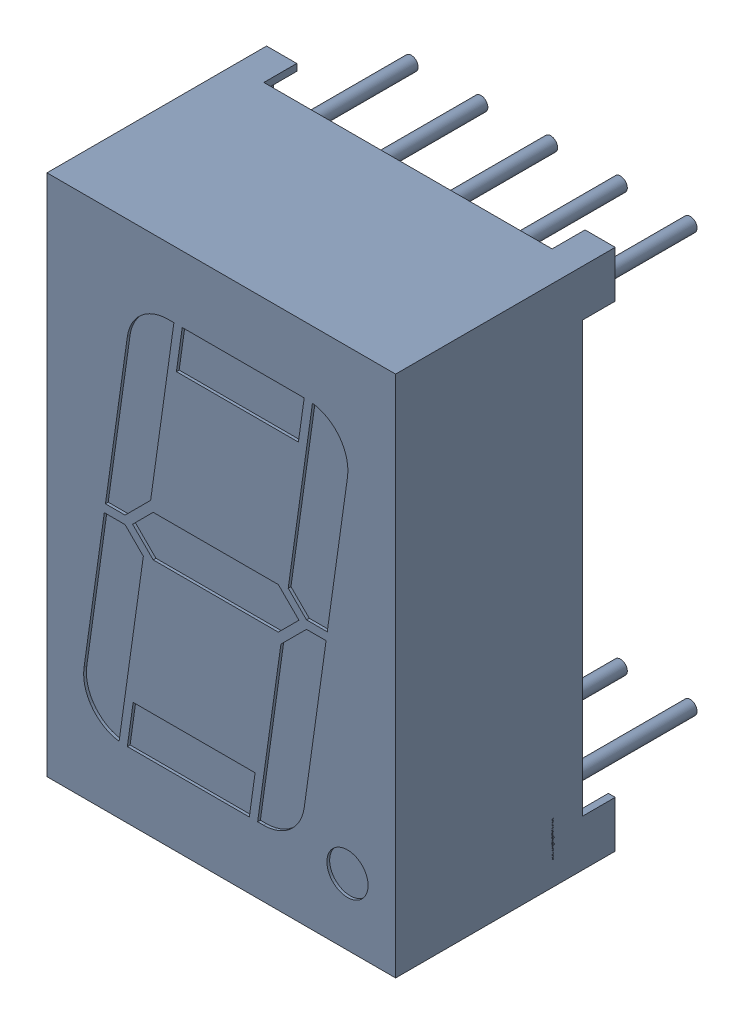
SolidWorks assembly Disp_SA56-11.1, configuration Default. Lengths in mm.
Overall size (12.7 19.05 12).
3 component instances, 1 part files, 0 mates.
Components (placement in the parent):
- SW3dPS-Disp_SA56-11-1: SW3dPS-Disp_SA56-11 [Default] at origin size (12.7 19.05 12)
  - SW3dPS-Disp_SA56-11_Open_CASCADE_STEP_translator_6.2_78.2-1: SW3dPS-Disp_SA56-11_Open_CASCADE_STEP_translator_6.2_78.2 [Default] at origin size (12.7 19.05 12)
    - SW3dPS-Disp_SA56-11_Disp_SA56-12_2-1: SW3dPS-Disp_SA56-11_Disp_SA56-12_2 [Default] at (5.0801 7.6201 8.0327) x (1 0 0) z (0 -1 0) size (12.7 12 19.05)
